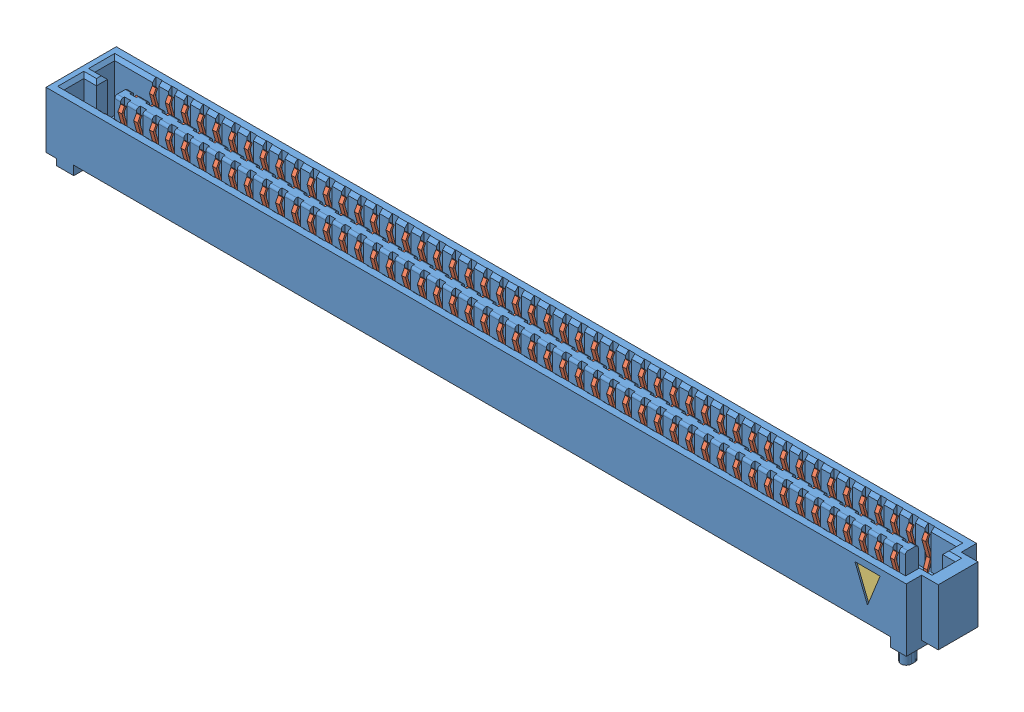
SolidWorks assembly SEAF_50_05_0_L_04_2_A_K_TR, configuration Default. Lengths in mm.
Overall size (70.66 6.32 5.66).
4 component instances, 4 part files, 0 mates.
Components (placement in the parent):
- _SEAF_50_05_0_L_04_1_A_0_K_TR_BODY_2_2-1: _SEAF_50_05_0_L_04_1_A_0_K_TR_BODY_2_2 [Default] at origin size (70.66 6.32 5.66)
- _SEAF_50_05_0_L_04_1_A_0_K_TR_cCON2_4-1: _SEAF_50_05_0_L_04_1_A_0_K_TR_cCON2_4 [Default] at origin size (62.55 4.65 5.41)
- _SEAF_04_K_PAD_6-1: _SEAF_04_K_PAD_6 [Default] at (-0.2286 4.318 0) size (6.5 0.13 6.5) (hidden)
- _SEAF_TRIANGLE_FIRST_PIN_8-1: _SEAF_TRIANGLE_FIRST_PIN_8 [Default] at (30.861 0.762 2.5781) size (2.03 2.54 0.13)
